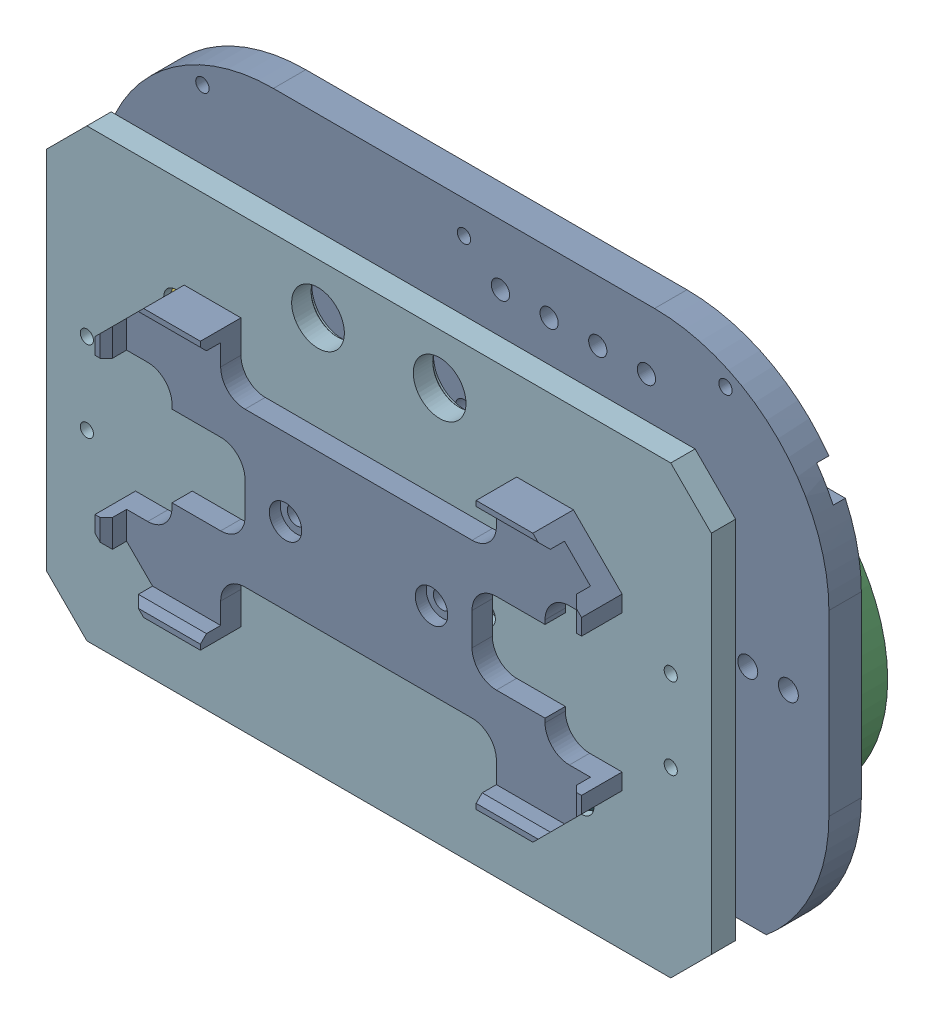
SolidWorks assembly _Werkst_X2_00FC_X0_cktr_X2_00E4_X0_ger, configuration Default. Lengths in mm.
Overall size (180 130 61.5).
29 component instances, 13 part files, 0 mates.
Components (placement in the parent):
- 014-055a_Werkst_X2_00FC_X0_cktr_X2_00E4_X0_ger-80_E-Band-mit Fixierbolzen-1: 014-055a_Werkst_X2_00FC_X0_cktr_X2_00E4_X0_ger-80_E-Band-mit Fixierbolzen [Default] at origin size (180 130 36.5)
  - 014-119b_Grundtr_X2_00E4_X0_ger-80_E-Band-1: 014-119b_Grundtr_X2_00E4_X0_ger-80_E-Band [Default] at origin size (180 130 8)
  - 014-133_Scheibe d80-1: 014-133_Scheibe d80 [Default] at (-50 0 0) x (1 0 0) z (0 0 -1) size (80 80 7.5)
  - 014-133_Scheibe d80-2: 014-133_Scheibe d80 [Default] at (50 0 0) x (1 0 0) z (0 0 -1) size (80 80 7.5)
  - DIN 915 - M5 x 8-1: DIN 915 - M5 x 8 [Default] at (45 50 0) x (0 0 1) z (-1 0 0) (suppressed, hidden)
  - DIN 915 - M5 x 8-2: DIN 915 - M5 x 8 [Default] at (33 50 0) x (0 0 1) z (-1 0 0) (suppressed, hidden)
  - DIN 915 - M5 x 8-3: DIN 915 - M5 x 8 [Default] at (21 50 0) x (0 0 1) z (-1 0 0) (suppressed, hidden)
  - DIN 915 - M5 x 8-4: DIN 915 - M5 x 8 [Default] at (9 50 0) x (0 0 1) z (-1 0 0) (suppressed, hidden)
  - DIN 7991 - M6x12-1: DIN 7991 - M6x12 [Default] at (-50 0 -6.95) x (0 -1 0) z (0 0 -1) (suppressed, hidden)
  - DIN 7991 - M6x12-2: DIN 7991 - M6x12 [Default] at (50 0 -6.95) x (0 -1 0) z (0 0 -1) (suppressed, hidden)
  - 014-132_Abstandshalter-Auflage-1: 014-132_Abstandshalter-Auflage [Default] at (-50 -28 8) size (12 12 17.8)
  - 014-132_Abstandshalter-Auflage-2: 014-132_Abstandshalter-Auflage [Default] at (50 28 8) size (12 12 17.8)
  - 014-132_Abstandshalter-Fang-1: 014-132_Abstandshalter-Fang [Default] at (-50 28 8) size (12 12 23.8)
  - 014-132_Abstandshalter-Fang-2: 014-132_Abstandshalter-Fang [Default] at (50 -28 8) size (12 12 23.8)
  - ISO 7380 - M4 x 10-1: ISO 7380 - M4 x 10 [Default] at (-50 -28 3) x (0 0 1) z (0 1 0) size (12.2 7.6 7.6)
  - ISO 7380 - M4 x 10-2: ISO 7380 - M4 x 10 [Default] at (-50 28 3) x (0 0 1) z (0 1 0) size (12.2 7.6 7.6)
  - ISO 7380 - M4 x 10-3: ISO 7380 - M4 x 10 [Default] at (50 -28 3) x (0 0 1) z (0.842401 0.538852 0) size (12.2 7.6 7.6)
  - ISO 7380 - M4 x 10-4: ISO 7380 - M4 x 10 [Default] at (50 28 3) x (0 0 1) z (0 1 0) size (12.2 7.6 7.6)
  - TW-R16-B128_RFID-Datentr_X2_00E4_X0_ger-1: TW-R16-B128_RFID-Datentr_X2_00E4_X0_ger [Default] at (-8 55 1.5) x (1 0 0) z (0 1 0) (suppressed, hidden)
- 014-102A_PALETTE_KOMPLETT-1: 014-102A_PALETTE_KOMPLETT [Default] at (0 0 23) size (164 110 16)
  - 014-102a_Palette 110x164mm-1: 014-102a_Palette 110x164mm [Default] at origin size (164 110 6)
  - 071-903_Aufnahmevorrichtung-1: 071-903_Aufnahmevorrichtung [Default] at (0 0 6) x (-1 0 0) z (0 0 1) size (120 66 10)
  - ISO 7380 - M4 x 8-1: ISO 7380 - M4 x 8 [Default] at (18 0 8.3) x (0 0 -1) z (0.009675 0.999953 0) (suppressed, hidden)
  - ISO 7380 - M4 x 8-2: ISO 7380 - M4 x 8 [Default] at (-18 0 8.3) x (0 0 -1) z (0.00137 0.999999 0) (suppressed, hidden)
  - 014-105a_iCIM-Aufnahmebolzen-1: 014-105a_iCIM-Aufnahmebolzen [Default] at (-15 42.5 0.2) x (1 -0.000438 0) z (0 0 1) (suppressed, hidden)
  - 014-105a_iCIM-Aufnahmebolzen-2: 014-105a_iCIM-Aufnahmebolzen [Default] at (15 42.5 0.2) (suppressed, hidden)
  - _WERKST_X2_00FC_X0_CK-RAISONANCE-KOMPLETT_1-1: _WERKST_X2_00FC_X0_CK-RAISONANCE-KOMPLETT_1 [Default] at (-57 30 31) x (1 0 0) z (0 0 -1) (suppressed, hidden)
  - _Reflektorfolie-1: _Reflektorfolie [Default] at (-62 51 6) (suppressed, hidden)
  - _Reflektorfolie-2: _Reflektorfolie [Default] at (62 -51 6) (suppressed, hidden)
